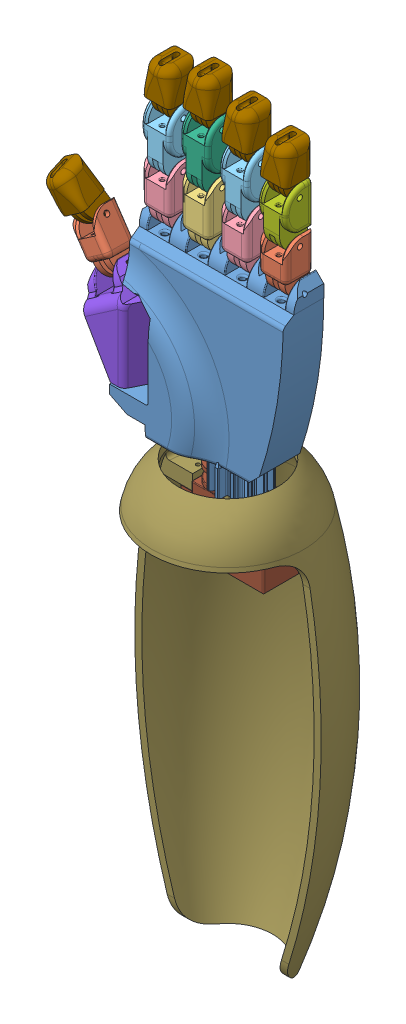
SolidWorks assembly Assem1, configuration Default. Lengths in mm.
Overall size (146.52 431.89 96.34).
19 component instances, 12 part files, 66 mates.
Components (placement in the parent):
- Part1-1: Part1 [Default] at (27.3416 18.0831 98.6011) size (91.41 116.29 35.29)
- Part2 - 1-1: Part2 - 1 [Default] at (81.7648 109.8831 101.1011) size (16 31 16)
- Part2-1: Part2 [Default] at (37.7648 109.8831 101.1011) size (16 38 16)
- Part2 - 2-1: Part2 - 2 [Default] at (59.7648 109.8831 101.1011) size (16 35 16)
- Part2 - 2-2: Part2 - 2 [Default] at (15.7648 109.8831 101.1011) size (16 35 16)
- Part2 - 2'-1: Part2 - 2' [Default] at (16.7648 136.3831 101.1011) size (16 36.15 16)
- Part2'-2: Part2' [Default] at (38.7648 139.3831 101.1011) size (16 38.15 16)
- Part2 - 1'-2: Part2 - 1' [Default] at (82.7648 132.3831 101.185) size (16 34.15 16)
- Part2 - 2'-2: Part2 - 2' [Default] at (60.7648 136.3831 101.1011) size (16 36.15 16)
- Part3-1: Part3 [Default] at (13.3521 77.0831 98.5848) size (34 49.56 30)
- Part2 - 1-2: Part2 - 1 [Default] at (-6.6601 71.7314 104.6306) x (0.822986 0.568062 0) z (-0.005158 0.007473 0.999959) size (16 31 16)
- Part4-1: Part4 [Default] at (-12.548 97.8652 103.4786) x (0.822986 0.568062 0) z (0.150538 -0.218094 0.964248) size (16.94 30.09 16.47)
- Part4-2: Part4 [Default] at (91.7648 156.3831 101.185) size (16.94 30.09 16.47)
- Part4-3: Part4 [Default] at (69.7648 162.3831 101.1011) size (16.94 30.09 16.47)
- Part4-4: Part4 [Default] at (47.7648 167.8831 101.1011) size (16.94 30.09 16.47)
- Part4-5: Part4 [Default] at (25.7648 162.3831 101.1011) size (16.94 30.09 16.47)
- pigno m-1: pigno m [Default] at (43.6511 16.2831 98.6011) x (-0.071971 0 0.997407) z (0 -1 0) size (20 20 15)
- Servo Motor MG996R-1: Servo Motor MG996R [Défaut] at (33.4011 -46.1169 108.8511) size (56.8 47.4 21)
- bra-1: bra [Default] at (53.9927 12.0831 108.6011) x (1 0 0) z (0 0 -1) size (105.65 252 96.34)
Mates (geometry in assembly coordinates):
- Concentric10: concentric aligned: cylinder of Part2-1 through (35.2648 143.8831 109.1011) axis (1 0 0) radius 1.5; cylinder of Part2'-2 through (35.2648 143.8831 109.1011) axis (1 0 0) radius 1.5
- Concentric12: concentric aligned: cylinder of Part2 - 2-2 through (13.2648 140.8831 109.1011) axis (1 0 0) radius 1.5; cylinder of Part2 - 2'-1 through (13.2648 140.8831 109.1011) axis (1 0 0) radius 1.5
- Concentric13: concentric aligned: cylinder of Part2 - 2-1 through (57.2648 140.8831 109.1011) axis (1 0 0) radius 1.5; cylinder of Part2 - 2'-2 through (57.2648 140.8831 109.1011) axis (1 0 0) radius 1.5
- Concentric14: concentric aligned: cylinder of Part2 - 1-1 through (79.2648 136.8831 109.1011) axis (1 0 0) radius 1.5; cylinder of Part2 - 1'-2 through (79.2648 136.8831 109.1011) axis (1 0 0) radius 1.5
- Width5: width anti-aligned: plane of Part2 - 2-2 through (16.2648 144.8831 117.1011) normal (1 0 0); plane of Part2 - 2'-1 through (26.2648 134.8831 117.1011) normal (-1 0 0); plane of Part2 - 2-2 through (16.7648 136.3831 117.1011) normal (-1 0 0); plane of Part2 - 2'-1 through (25.7648 146.3831 117.1011) normal (1 0 0)
- Width6: width anti-aligned: plane of Part2-1 through (38.2648 147.8831 117.1011) normal (1 0 0); plane of Part2'-2 through (48.2648 137.8831 117.1011) normal (-1 0 0); plane of Part2-1 through (38.7648 139.3831 117.1011) normal (-1 0 0); plane of Part2'-2 through (47.7648 149.3831 117.1011) normal (1 0 0)
- Width7: width anti-aligned: plane of Part2 - 2-1 through (60.2648 144.8831 117.1011) normal (1 0 0); plane of Part2 - 2'-2 through (70.2648 134.8831 117.1011) normal (-1 0 0); plane of Part2 - 2-1 through (60.7648 136.3831 117.1011) normal (-1 0 0); plane of Part2 - 2'-2 through (69.7648 146.3831 117.1011) normal (1 0 0)
- Width8: width anti-aligned: plane of Part2 - 1-1 through (92.2648 130.8831 117.1011) normal (-1 0 0); plane of Part2 - 1'-2 through (82.2648 140.8831 117.1011) normal (1 0 0); plane of Part2 - 1-1 through (91.7648 142.3831 117.185) normal (1 0 0); plane of Part2 - 1'-2 through (82.7648 132.3831 117.185) normal (-1 0 0)
- Concentric15: concentric aligned: cylinder of Part1-1 through (17.3521 18.0831 113.5848) axis (0 1 0) radius 1.5; cylinder of Part3-1 through (17.3521 36.0831 113.5848) axis (0 1 0) radius 1.5
- Width9: width anti-aligned: plane of Part1-1 through (21.8521 35.0831 128.6011) normal (0 1 0); plane of Part1-1 through (12.8521 78.0831 128.6011) normal (0 -1 0); plane of Part3-1 through (21.3521 36.0831 128.5848) normal (0 -1 0); plane of Part3-1 through (13.3521 77.0831 128.5848) normal (0 1 0)
- Concentric16: concentric aligned: cylinder of Part3-1 through (-30.2629 61.6031 112.5848) axis (0.822986 0.568062 0) radius 1.5; cylinder of Part2 - 1-2 through (-11.5991 74.4857 112.5848) axis (0.822986 0.568062 0) radius 1.5
- Width10: width aligned: plane of Part3-1 through (-2.6336 86.1421 128.5848) normal (-0.822986 -0.568062 0); plane of Part3-1 through (-5.6926 69.4495 128.5848) normal (0.822986 0.568062 0); plane of Part2 - 1-2 through (-6.7427 71.8509 120.6299) normal (-0.822986 -0.568062 0); plane of Part2 - 1-2 through (-3.3702 86.3291 120.5391) normal (0.822986 0.568062 0)
- Concentric17: concentric anti-aligned: cylinder of Part2 - 1-2 through (-24.0959 92.5907 112.3851) axis (0.822986 0.568062 0) radius 1.5; cylinder of Part4-1 through (-10.5413 101.9467 112.3851) axis (-0.822986 -0.568062 0) radius 1.5
- Width11: width anti-aligned: plane of Part2 - 1-2 through (-23.9404 97.6465 120.3484) normal (0.822986 0.568062 0); plane of Part2 - 1-2 through (-10.0301 95.0976 120.4392) normal (-0.822986 -0.568062 0); plane of Part4-1 through (-24.1193 98.7859 122.0866) normal (-0.822986 -0.568062 0); plane of Part4-1 through (-10.1394 94.3757 118.9065) normal (0.822986 0.568062 0)
- Concentric19: concentric anti-aligned: cylinder of Part2 - 2'-2 through (57.2648 166.8831 109.1011) axis (1 0 0) radius 1.5; cylinder of Part4-3 through (73.7349 166.8831 109.1011) axis (-1 0 0) radius 1.5
- Concentric20: concentric anti-aligned: cylinder of Part2'-2 through (35.2648 172.3831 109.1011) axis (1 0 0) radius 1.5; cylinder of Part4-4 through (51.7349 172.3831 109.1011) axis (-1 0 0) radius 1.5
- Coincident1: coincident anti-aligned: cylinder of Part2 - 2'-1 through (13.2648 166.8831 109.1011) axis (1 0 0) radius 1.5; circle of Part4-5
- Width12: width aligned: plane of Part2 - 2'-1 through (16.2648 172.3831 117.1011) normal (1 0 0); plane of Part2 - 2'-1 through (26.2648 161.3831 117.1011) normal (-1 0 0); plane of Part4-5 through (25.7648 162.3831 117.1011) normal (1 0 0); plane of Part4-5 through (16.7648 174.3831 117.1011) normal (-1 0 0)
- Width13: width anti-aligned: plane of Part2'-2 through (38.2648 177.3831 117.1011) normal (1 0 0); plane of Part2'-2 through (48.2648 167.3831 117.1011) normal (-1 0 0); plane of Part4-4 through (38.7648 179.8831 117.1011) normal (-1 0 0); plane of Part4-4 through (47.7648 167.8831 117.1011) normal (1 0 0)
- Width14: width anti-aligned: plane of Part2 - 2'-2 through (60.2648 172.3831 117.1011) normal (1 0 0); plane of Part2 - 2'-2 through (70.2648 161.3831 117.1011) normal (-1 0 0); plane of Part4-3 through (60.7648 174.3831 117.1011) normal (-1 0 0); plane of Part4-3 through (69.7648 162.3831 117.1011) normal (1 0 0)
- Width15: width anti-aligned: plane of Part2 - 1'-2 through (82.2648 166.3831 117.185) normal (1 0 0); plane of Part2 - 1'-2 through (92.2648 155.3831 117.185) normal (-1 0 0); plane of Part4-2 through (82.7648 168.3831 117.185) normal (-1 0 0); plane of Part4-2 through (91.7648 156.3831 117.185) normal (1 0 0)
- Concentric21: concentric anti-aligned: cylinder of Part2 - 1'-2 through (79.2648 160.8831 109.185) axis (1 0 0) radius 1.5; cylinder of Part4-2 through (95.7349 160.8831 109.185) axis (-1 0 0) radius 1.5
- Concentric22: concentric aligned: cylinder of Part1-1 through (6.8521 114.8831 109.1011) axis (1 0 0) radius 1.25; cylinder of Part2 - 1-1 through (79.2648 114.8831 109.1011) axis (1 0 0) radius 1.5
- Concentric23: concentric aligned: cylinder of Part1-1 through (6.8521 114.8831 109.1011) axis (1 0 0) radius 1.25; cylinder of Part2 - 2-1 through (57.2648 114.8831 109.1011) axis (1 0 0) radius 1.5
- Concentric24: concentric aligned: cylinder of Part1-1 through (6.8521 114.8831 109.1011) axis (1 0 0) radius 1.25; cylinder of Part2-1 through (35.2648 114.8831 109.1011) axis (1 0 0) radius 1.5
- Concentric25: concentric aligned: cylinder of Part1-1 through (6.8521 114.8831 109.1011) axis (1 0 0) radius 1.25; cylinder of Part2 - 2-2 through (13.2648 114.8831 109.1011) axis (1 0 0) radius 1.5
- Width16: width anti-aligned: plane of Part1-1 through (27.2648 120.0831 128.6011) normal (-1 0 0); plane of Part1-1 through (15.2648 108.0831 128.6011) normal (1 0 0); plane of Part2 - 2-2 through (26.7648 119.8831 117.1011) normal (1 0 0); plane of Part2 - 2-2 through (15.7648 109.8831 117.1011) normal (-1 0 0)
- Width17: width anti-aligned: plane of Part1-1 through (49.2648 108.0831 128.6011) normal (-1 0 0); plane of Part1-1 through (37.2648 108.0831 128.6011) normal (1 0 0); plane of Part2-1 through (48.7648 119.8831 117.1011) normal (1 0 0); plane of Part2-1 through (37.7648 109.8831 117.1011) normal (-1 0 0)
- Width18: width anti-aligned: plane of Part1-1 through (71.2648 120.0831 128.6011) normal (-1 0 0); plane of Part1-1 through (59.2648 120.0831 128.6011) normal (1 0 0); plane of Part2 - 2-1 through (70.7648 119.8831 117.1011) normal (1 0 0); plane of Part2 - 2-1 through (59.7648 109.8831 117.1011) normal (-1 0 0)
- Width19: width anti-aligned: plane of Part1-1 through (93.2648 120.0831 128.6011) normal (-1 0 0); plane of Part1-1 through (81.2648 108.0831 128.6011) normal (1 0 0); plane of Part2 - 1-1 through (92.7648 119.8831 117.1011) normal (1 0 0); plane of Part2 - 1-1 through (81.7648 109.8831 117.1011) normal (-1 0 0)
- Concentric26: concentric anti-aligned: cylinder of pigno m-1 through (43.6511 1.2831 98.6011) axis (0 1 0) radius 0.5; cylinder of Servo Motor MG996R-1 through (43.6511 1.2831 98.6011) axis (0 -1 0) radius 10.5
- Coincident3: coincident anti-aligned: plane of pigno m-1 through (43.6511 1.2831 98.6011) normal (0 -1 0); plane of Servo Motor MG996R-1 through (43.6511 1.2831 98.6011) normal (0 1 0)
- Parallel2: parallel anti-aligned: plane of Part1-1 through (-164.0423 108.0831 98.6011) normal (0 0 -1); plane of bra-1 through (-2.0499 -13.4169 108.6011) normal (0 0 1)
- Concentric32: concentric aligned: cylinder of Servo Motor MG996R-1 through (29.9011 -46.1169 93.6011) axis (0 1 0) radius 2.1; cylinder of bra-1 through (29.9011 -6.4169 93.6011) axis (0 1 0) radius 1.05
- Concentric33: concentric aligned: cylinder of Servo Motor MG996R-1 through (77.9011 -46.1169 93.6011) axis (0 1 0) radius 2.1; cylinder of bra-1 through (77.9011 -14.9169 93.6011) axis (0 1 0) radius 1.05
- Coincident6: coincident anti-aligned: plane of Servo Motor MG996R-1 through (26.6011 -14.9169 89.3511) normal (0 1 0); plane of bra-1 through (53.9927 -14.9169 108.6011) normal (0 -1 0)
- Concentric34: concentric aligned: cylinder of Part1-1 through (61.4849 3.0831 108.6011) axis (0 1 0) radius 7.5; cylinder of bra-1 through (61.4849 18.0831 108.6011) axis (0 1 0) radius 7
- Coincident8: coincident anti-aligned: plane of Part1-1 through (27.3416 18.0831 128.6011) normal (0 -1 0); plane of bra-1 through (61.4849 18.0831 108.6011) normal (0 1 0)
- AngleLimite3: limit planar angle = 1.711411 rad anti-aligned: plane of Part4-2 through (91.7648 156.3831 117.185) normal (0 0 1); plane of Part2 - 1'-2 through (82.7648 132.3831 117.185) normal (0 0 1)
- AngleLimite4: limit planar angle = 1.972222 rad anti-aligned: plane of Part2 - 1'-2 through (82.7648 132.3831 117.185) normal (0 0 1); plane of Part2 - 1-1 through (81.7648 109.8831 117.1011) normal (0 0 1)
- AngleLimite6: limit planar angle = 1.832596 rad anti-aligned: plane of Part2 - 1-1 through (81.7648 109.8831 117.1011) normal (0 0 1); plane of Part1-1 through (6.8521 18.0831 121.6011) normal (0 0 1)
- AngleLimite7: limit planar angle = 3.193953 rad anti-aligned: plane of Part4-3 through (69.7648 162.3831 117.1011) normal (0 0 1); plane of Part2 - 2'-2 through (60.7648 136.3831 117.1011) normal (0 0 1)
- AngleLimite8: limit planar angle = 3.333579 rad anti-aligned: plane of Part2 - 2'-2 through (60.7648 136.3831 117.1011) normal (0 0 1); plane of Part2 - 2-1 through (59.7648 109.8831 117.1011) normal (0 0 1)
- AngleLimite9: limit planar angle = 3.333579 rad anti-aligned: plane of Part2 - 2-1 through (59.7648 109.8831 117.1011) normal (0 0 1); plane of Part1-1 through (6.8521 18.0831 121.6011) normal (0 0 1)
- AngleLimite10: limit planar angle = 3.193953 rad anti-aligned: plane of Part4-4 through (47.7648 167.8831 117.1011) normal (0 0 1); plane of Part2'-2 through (38.7648 139.3831 117.1011) normal (0 0 1)
- AngleLimite11: limit planar angle = 3.333579 rad anti-aligned: plane of Part2'-2 through (38.7648 139.3831 117.1011) normal (0 0 1); plane of Part2-1 through (37.7648 109.8831 117.1011) normal (0 0 1)
- AngleLimite15: limit planar angle = 3.333579 rad anti-aligned: plane of Part2-1 through (37.7648 109.8831 117.1011) normal (0 0 1); plane of Part1-1 through (6.8521 18.0831 121.6011) normal (0 0 1)
- AngleLimite16: limit planar angle = 3.193953 rad anti-aligned: plane of Part4-5 through (25.7648 162.3831 117.1011) normal (0 0 1); plane of Part2 - 2'-1 through (16.7648 136.3831 117.1011) normal (0 0 1)
- AngleLimite17: limit planar angle = 3.333579 rad anti-aligned: plane of Part2 - 2'-1 through (16.7648 136.3831 117.1011) normal (0 0 1); plane of Part2 - 2-2 through (15.7648 109.8831 117.1011) normal (0 0 1)
- AngleLimite18: limit planar angle = 3.333579 rad anti-aligned: plane of Part2 - 2-2 through (15.7648 109.8831 117.1011) normal (0 0 1); plane of Part1-1 through (6.8521 18.0831 121.6011) normal (0 0 1)
- AngleLimite19: limit planar angle = 2.027436 rad anti-aligned: plane of Part4-1 through (-9.8047 94.6182 120.5243) normal (0.207905 -0.178421 0.961739); plane of Part2 - 1-2 through (-6.2447 72.1847 122.9603) normal (0.053916 0.048327 0.997375)
- AngleLimite22: limit planar angle = 2.443461 rad anti-aligned: plane of Part2 - 1-2 through (-6.2447 72.1847 122.9603) normal (0.053916 0.048327 0.997375); plane of Part3-1 through (14.6768 77.0831 128.8768) normal (0.087297 0 0.996182)
- AngleLimite23: limit planar angle = 3.054185 rad anti-aligned: plane of Part1-1 through (-164.0423 108.0831 128.6011) normal (0 0 1); plane of Part3-1 through (14.6768 77.0831 128.8768) normal (0.087297 0 0.996182)
- Parallèle3: parallel aligned: plane of Part1-1 through (-164.0423 108.0831 98.6011) normal (0 0 -1); plane of Part4-2 through (91.7648 156.3831 101.185) normal (0 0 -1)
- Parallèle4: parallel aligned: plane of Part1-1 through (-164.0423 108.0831 98.6011) normal (0 0 -1); plane of Part4-3 through (69.7648 162.3831 101.1011) normal (0 0 -1)
- Parallèle5: parallel aligned: plane of Part1-1 through (-164.0423 108.0831 98.6011) normal (0 0 -1); plane of Part4-4 through (47.7648 167.8831 101.1011) normal (0 0 -1)
- Parallèle6: parallel aligned: plane of Part1-1 through (-164.0423 108.0831 98.6011) normal (0 0 -1); plane of Part4-5 through (25.7648 162.3831 101.1011) normal (0 0 -1)
- Parallèle7: parallel aligned: plane of Part1-1 through (27.3416 18.0831 118.6011) normal (0 0 -1); plane of Part2 - 1'-2 through (82.7648 132.3831 101.185) normal (0 0 -1)
- Parallèle8: parallel aligned: plane of Part1-1 through (27.3416 18.0831 118.6011) normal (0 0 -1); plane of Part2 - 2'-2 through (60.7648 136.3831 101.1011) normal (0 0 -1)
- Parallèle9: parallel aligned: plane of Part1-1 through (27.3416 18.0831 118.6011) normal (0 0 -1); plane of Part2'-2 through (38.7648 139.3831 101.1011) normal (0 0 -1)
- Parallèle10: parallel aligned: plane of Part1-1 through (27.3416 18.0831 118.6011) normal (0 0 -1); plane of Part2 - 2'-1 through (16.7648 136.3831 101.1011) normal (0 0 -1)
- Parallèle11: parallel aligned: plane of Part1-1 through (27.3416 18.0831 118.6011) normal (0 0 -1); plane of Part2 - 1-1 through (81.7648 109.8831 101.1011) normal (0 0 -1)
- Parallèle13: parallel aligned: plane of Part1-1 through (27.3416 18.0831 118.6011) normal (0 0 -1); plane of Part2 - 2-1 through (59.7648 109.8831 101.1011) normal (0 0 -1)
- Parallèle14: parallel aligned: plane of Part1-1 through (27.3416 18.0831 118.6011) normal (0 0 -1); plane of Part2-1 through (37.7648 109.8831 101.1011) normal (0 0 -1)
- Parallèle15: parallel aligned: plane of Part1-1 through (27.3416 18.0831 118.6011) normal (0 0 -1); plane of Part2 - 2-2 through (15.7648 109.8831 101.1011) normal (0 0 -1)
- Parallèle16: parallel aligned: plane of Part1-1 through (-164.0423 108.0831 98.6011) normal (0 0 -1); plane of Part3-1 through (13.3521 77.0831 98.5848) normal (0 0 -1)
